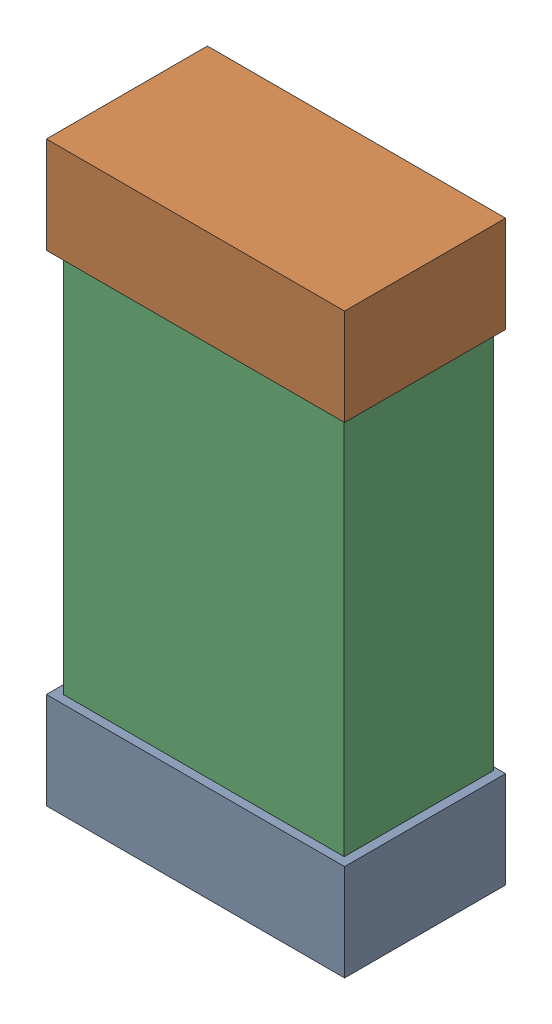
SolidWorks assembly R46, configuration Default. Lengths in mm.
Overall size (0.85 1.65 0.46).
6 component instances, 2 part files, 0 mates.
Components (placement in the parent):
- 432138512_12-1: 432138512_12 [Default] at (32.1833 42.8142 -0.8715) size (0.85 0.28 0.46)
  - Extruded-1: Extruded [Default] at origin size (0.85 0.28 0.46)
- 432138512_13-1: 432138512_13 [Default] at (32.1833 44.1857 -0.8715) size (0.85 0.28 0.46)
  - Extruded-1: Extruded [Default] at origin size (0.85 0.28 0.46)
- 432124816_6-1: 432124816_6 [Default] at (32.1833 43.4999 -0.8615) size (0.8 1.5 0.42)
  - Extruded (1)-1: Extruded (1) [Default] at origin size (0.8 1.5 0.42)
